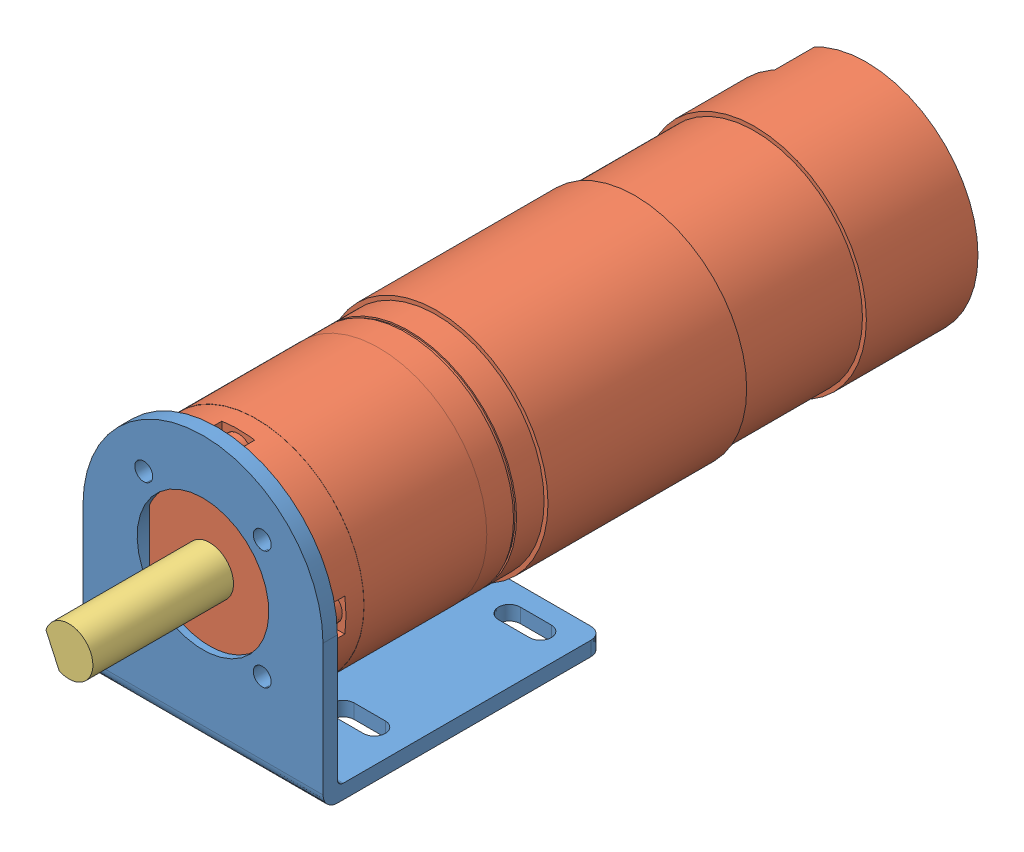
SolidWorks assembly Assem2, configuration Default. Lengths in mm.
Overall size (126.92 109.66 140.25).
4 component instances, 3 part files, 9 mates.
Components (placement in the parent):
- gá đỡ động cơ-2: gá đỡ động cơ [Default] at (0 24.35 0) x (0 1 0) z (0 0 1) size (44.4 40.1 46.8)
- DC planet geared motor-1: DC planet geared motor [Default] at (112.0851 33.9065 -59.6916) x (-0.239325 0.168703 -0.956171) z (-0.801829 0.521005 0.292618) size (136.62 52.79 81.46)
  - motor-1: motor [Default] at (-31.8628 68.735 102.3609) x (0.168703 -0.836716 0.521005) z (0.239325 0.547535 0.801829) size (37.3 109.75 37.3)
  - shaft-1: shaft [Default] at (-25.6477 68.8038 100.4589) x (-0.253239 0.531568 -0.808273) z (0.146993 0.84695 0.510949) size (8 31.3 8)
Mates (geometry in assembly coordinates):
- Coincident5: coincident anti-aligned: plane of motor-2 through (-21.6303 0 0) normal (0 -1 0)
- Coincident6: coincident anti-aligned: plane of motor-2 through (-21.6303 0 0) normal (0 0 -1)
- Coincident7: coincident anti-aligned: plane of motor-2 through (-21.6303 0 0) normal (-1 0 0)
- Coincident11: coincident anti-aligned: plane of gá đỡ động cơ-2 through (0 24.35 0) normal (0 0 -1); plane of DC planet geared motor-1/motor-1 through (0 24.35 0) normal (0 0 1)
- Coincident12: coincident anti-aligned: plane of gá đỡ động cơ-2 through (20.05 0 2.4) normal (0 -1 0)
- Coincident13: coincident anti-aligned: plane of gá đỡ động cơ-2 through (0 24.35 0) normal (-1 0 0)
- Coincident15: coincident aligned: plane of gá đỡ động cơ-2 through (0 24.35 0) normal (0 0 1)
- Concentric3: concentric anti-aligned: cylinder of gá đỡ động cơ-2 through (-9.8995 34.2495 2.4) axis (0 0 -1) radius 1.5; cylinder of DC planet geared motor-1/motor-1 through (-9.8995 34.2495 -10) axis (0 0 1) radius 1.5
- Concentric4: concentric anti-aligned: cylinder of gá đỡ động cơ-2 through (9.8995 34.2495 2.4) axis (0 0 -1) radius 1.5; cylinder of DC planet geared motor-1/motor-1 through (9.8995 34.2495 -10) axis (0 0 1) radius 1.5
